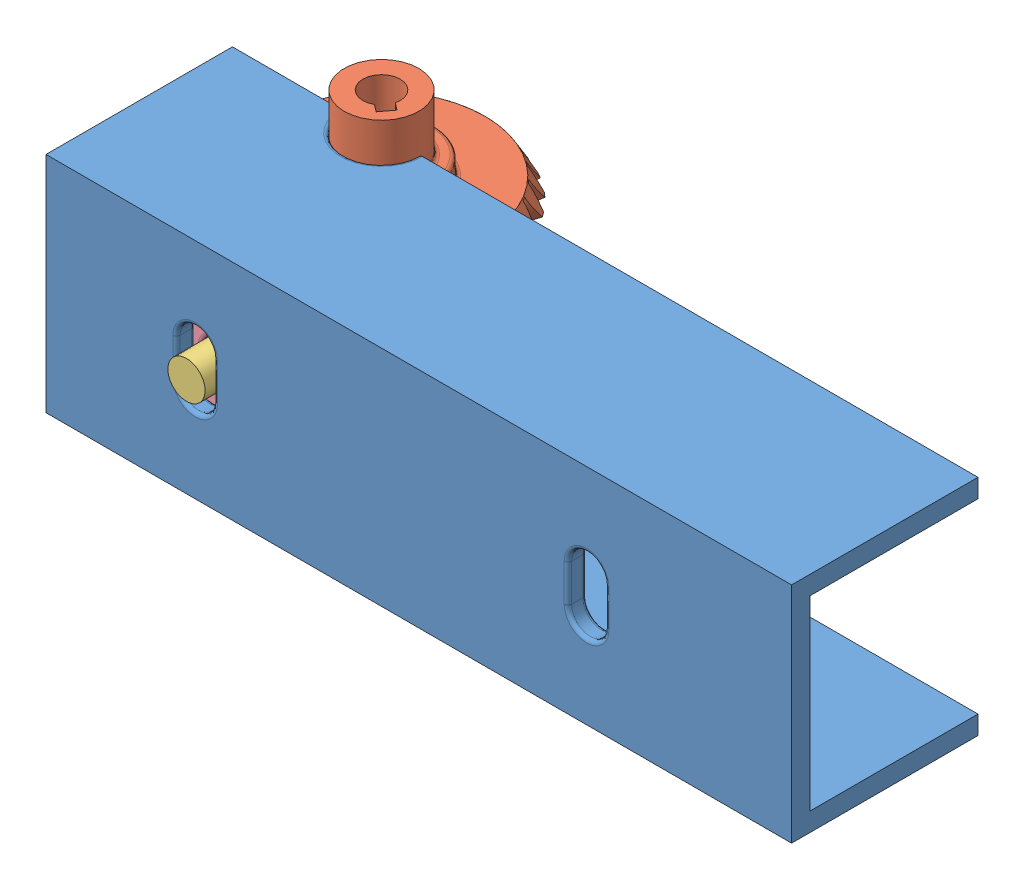
SolidWorks assembly ASSEMBLY Bevel Gear Test Attemp 3, configuration Default. Lengths in mm.
Overall size (203.39 98.06 95.74).
4 component instances, 4 part files, 8 mates.
Components (placement in the parent):
- Main Case-1: Main Case [Default] at (44.068 109.3733 166.2587) size (200 60 82.5)
- Secondary Main Bevel Gear-1: Secondary Main Bevel Gear [Default] at (-15.932 125.4762 166.2587) x (-0.602826 0 0.797873) z (0.797873 0 0.602826) size (61.95 69.28 62)
- Secondary Bevel Gear-1: Secondary Bevel Gear [Default] at (-15.932 108.1557 196.1366) x (-0.999694 0.024741 0) z (-0.024741 -0.999694 0) size (38.46 52.32 38.26)
- Main Spur Gear - Copy-1: Main Spur Gear - Copy [Default] at (-15.932 108.1557 204.5741) x (-0.137226 0.99054 0) z (0 0 1) size (32.38 32.33 10)
Mates (geometry in assembly coordinates):
- Concentric1: concentric anti-aligned: cylinder of Main Case-1 through (-15.932 129.3733 166.2587) axis (0 1 0) radius 10; cylinder of Secondary Main Bevel Gear-1 through (-15.932 149.3733 166.2587) axis (0 -1 0) radius 10
- Coincident1: coincident anti-aligned: plane of Main Case-1 through (-55.932 134.3733 216.2587) normal (0 -1 0); plane of Secondary Main Bevel Gear-1 through (-15.932 134.3733 166.2587) normal (0 1 0)
- Coincident2: coincident: point of Secondary Main Bevel Gear-1; point of Secondary Bevel Gear-1
- Perpendicular1: perpendicular: line of Secondary Main Bevel Gear-1 through (-15.932 108.1557 166.2587) axis (0 1 0); line of Secondary Bevel Gear-1 through (-15.932 108.1557 166.2587) axis (0 0 1)
- Parallel1: parallel aligned: plane of Main Case-1 through (44.068 109.3733 216.2587) normal (0 0 1); plane of Secondary Bevel Gear-1 through (-15.932 108.1557 218.5741) normal (0 0 1)
- Concentric2: concentric anti-aligned: cylinder of Secondary Bevel Gear-1 through (-15.932 108.1557 218.5741) axis (0 0 -1) radius 5; cylinder of Main Spur Gear - Copy-1 through (-15.932 108.1557 199.5741) axis (0 0 1) radius 5
- Distance1: distance = 1 mm anti-aligned: plane of Secondary Bevel Gear-1 through (-15.932 108.1557 198.5741) normal (0 0 1); plane of Main Spur Gear - Copy-1 through (-15.932 108.1557 199.5741) normal (0 0 -1)
- GearMate1: gear = 60 : 34.5 mm: circle of Secondary Bevel Gear-1; circle of Secondary Main Bevel Gear-1
